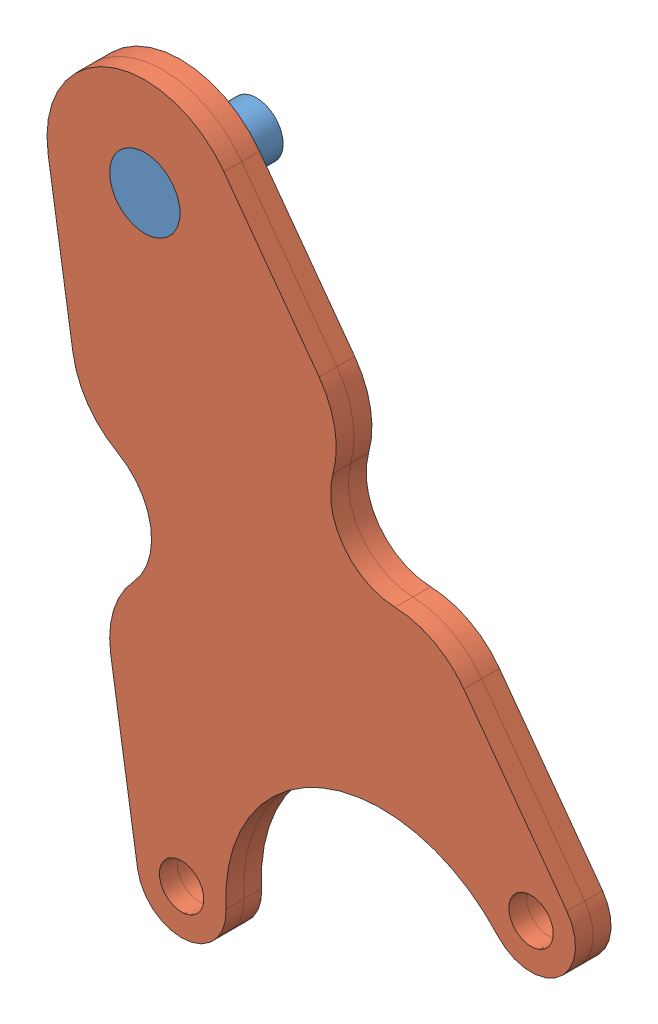
SolidWorks assembly ТП.002.05.01.00 - Наружняя качалка, configuration Прямой вырез. Lengths in mm.
Overall size (156.75 184.32 29.05).
5 component instances, 3 part files, 5 mates.
Components (placement in the parent):
- ТП.002.05.01.01 - Ось качалки-1: ТП.002.05.01.01 - Ось качалки [00] at origin size (15.8 15.8 25.05)
- ТП.002.05.01.02 - КАЧАЛКА-1: ТП.002.05.01.02 - КАЧАЛКА [По умолчанию] x (-0.923728 -0.383049 0) z (0 0 -1) size (105 156 8) (hidden)
- ТП.002.05.03.00 - Качалка управляющая-1: ТП.002.05.03.00 - Качалка управляющая [00] at (13.1386 -31.6839 4) x (-0.923728 -0.383049 0) z (0 0 -1) size (105 156 12)
  - ТП.002.05.01.01 - Качалка управляющая-1: ТП.002.05.01.01 - Качалка управляющая [Глухая] at origin size (105 156 12)
  - ТП.002.05.01.01 - Качалка управляющая-2: ТП.002.05.01.01 - Качалка управляющая [С вырезом] at origin size (105 156 12)
Mates (geometry in assembly coordinates):
- Концентричный1: concentric: cylinder of ТП.002.05.01.01 - Ось качалки-1 through (0 0 -39.3946) axis (0 0 1) radius 7.9; cylinder of ТП.002.05.01.02 - КАЧАЛКА-1 through (0 0 -8) axis (0 0 1) radius 7.9
- Совпадение1: coincident: plane of ТП.002.05.01.01 - Ось качалки-1 through (0 0 0) normal (0 0 1); plane of ТП.002.05.01.02 - КАЧАЛКА-1 through (53.1634 -128.2044 0) normal (0 0 1)
- Концентричный2: concentric: cylinder of ТП.002.05.01.01 - Ось качалки-1 through (0 0 -39.3946) axis (0 0 1) radius 7.9; cylinder of ТП.002.05.03.00 - Качалка управляющая-1/ТП.002.05.01.01 - Качалка управляющая-1 through (0 0 0) axis (0 0 -1) radius 7.9
- Совпадение2: coincident: plane of ТП.002.05.01.02 - КАЧАЛКА-1 through (53.1634 -128.2044 -8) normal (0 0 -1); plane of ТП.002.05.03.00 - Качалка управляющая-1/ТП.002.05.01.01 - Качалка управляющая-2 through (53.1634 -128.2044 -8) normal (0 0 -1)
- Концентричный3: concentric: cylinder of ТП.002.05.01.02 - КАЧАЛКА-1 through (86.7565 -98.2627 -8) axis (0 0 1) radius 5; cylinder of ТП.002.05.03.00 - Качалка управляющая-1/ТП.002.05.01.01 - Качалка управляющая-2 through (86.7565 -98.2627 -8) axis (0 0 1) radius 5
